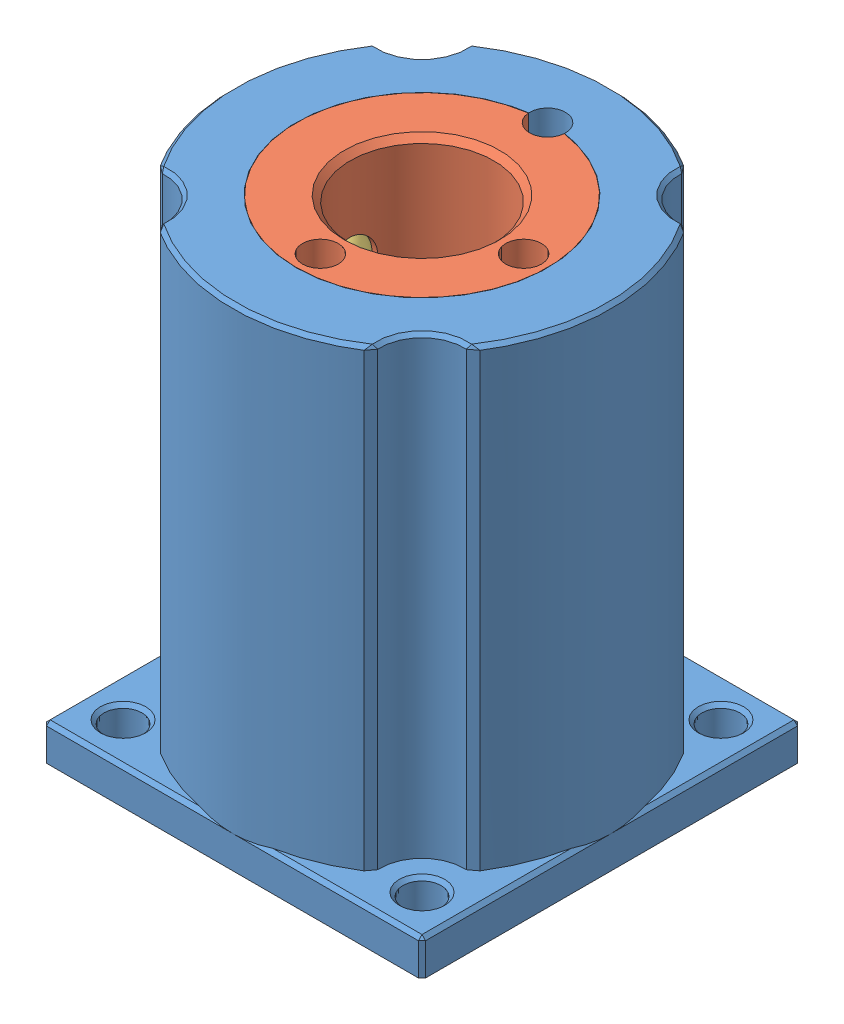
SolidWorks assembly New laser incoupler, configuration Default. Lengths in mm.
Overall size (31.7 41 31.7).
6 component instances, 4 part files, 11 mates.
Components (placement in the parent):
- in coupler-1: in coupler [Default] at (9.3737 -6.068 38.3523) size (31.7 41 31.7)
- in coupler insert-1: in coupler insert [Default] at (9.3737 -3.068 38.3523) size (21 38 21)
- 3-16in steel ball-1: 3-16in steel ball [Default] at (1.8375 3.932 38.3523) x (0.568361 0.821082 -0.052813) z (-0.819572 0.559316 -0.124369) size (4.76 4.76 4.76)
- 3-16in steel ball-2: 3-16in steel ball [Default] at (1.8375 26.932 38.3523) x (-0.957727 -0.083912 0.275168) z (0.285332 -0.15517 0.945784) size (4.76 4.76 4.76)
- M6x1.0x4 set screw mock up-1: M6x1.0x4 set screw mock up [Default] at (-2.4763 26.932 38.3523) x (0 0.935585 -0.353101) z (0 0.353101 0.935585) size (6 4 6)
- M6x1.0x4 set screw mock up-2: M6x1.0x4 set screw mock up [Default] at (-6.4763 3.932 38.3523) x (0 0.572959 -0.819584) z (0 -0.819584 -0.572959) size (6 4 6)
Mates (geometry in assembly coordinates):
- Concentric1: concentric anti-aligned: cylinder of in coupler-1 through (9.3737 -32.8372 38.3523) axis (0 1 0) radius 10.525; cylinder of in coupler insert-1 through (9.3737 34.932 38.3523) axis (0 -1 0) radius 10.5
- Coincident1: coincident anti-aligned: plane of in coupler-1 through (9.3737 -3.068 38.3523) normal (0 1 0); plane of in coupler insert-1 through (9.3737 -3.068 38.3523) normal (0 -1 0)
- Coincident2: coincident aligned: plane of in coupler-1 through (9.3737 -6.068 38.3523) normal (0 0 1); plane of in coupler insert-1 through (9.3737 -3.068 38.3523) normal (0 0 1)
- Concentric2: concentric: cylinder of in coupler insert-1 through (-1.1263 26.932 38.3523) axis (-1 0 0) radius 2.5; sphere of 3-16in steel ball-2
- Coincident4: coincident: circle of in coupler insert-1; sphere of 3-16in steel ball-2
- Concentric3: concentric: cylinder of in coupler insert-1 through (-1.1263 3.932 38.3523) axis (-1 0 0) radius 2.5; sphere of 3-16in steel ball-1
- Coincident5: coincident: circle of in coupler insert-1; sphere of 3-16in steel ball-1
- Concentric6: concentric aligned: cylinder of in coupler-1 through (-6.4763 3.932 38.3523) axis (-1 0 0) radius 2.5; cylinder of M6x1.0x4 set screw mock up-2 through (-2.4763 3.932 38.3523) axis (-1 0 0) radius 3
- Concentric7: concentric anti-aligned: cylinder of in coupler-1 through (-6.4763 26.932 38.3523) axis (-1 0 0) radius 2.5; cylinder of M6x1.0x4 set screw mock up-1 through (-6.4763 26.932 38.3523) axis (1 0 0) radius 3
- Coincident6: coincident aligned: plane of in coupler-1 through (-6.4763 -3.068 54.2023) normal (-1 0 0); plane of M6x1.0x4 set screw mock up-1 through (-6.4763 26.932 38.3523) normal (-1 0 0)
- Coincident7: coincident anti-aligned: plane of in coupler-1 through (-6.4763 -3.068 54.2023) normal (-1 0 0); circle of M6x1.0x4 set screw mock up-2
